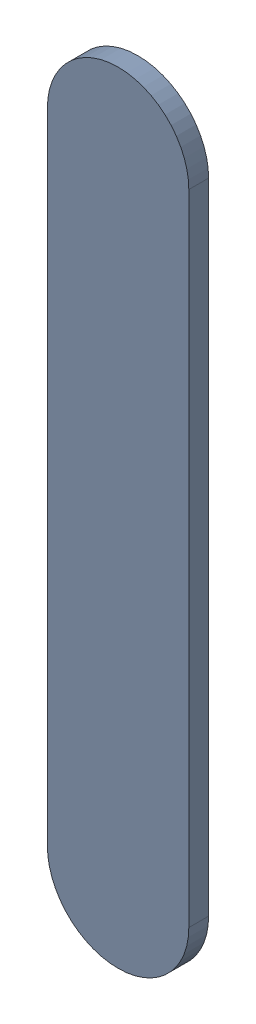
SolidWorks assembly Track (20.574mm,53.426mm)(20.574mm,54.574mm) on Bottom Layer, configuration Predeterminado. Lengths in mm.
Overall size (0.25 1.4 0.04).
2 component instances, 1 part files, 0 mates.
Components (placement in the parent):
- Track (20.574mm,53.426mm)(20.574mm,54.574mm) on Bottom Layer-1-1: Track (20.574mm,53.426mm)(20.574mm,54.574mm) on Bottom Layer-1 [Predeterminado] at (-68.317 -44.187 -0.4013) size (0.25 1.4 0.04)
  - Track (20.574mm,53.426mm)(20.574mm,54.574mm) on Bottom Layer-Part-1-1: Track (20.574mm,53.426mm)(20.574mm,54.574mm) on Bottom Layer-Part-1 [Predeterminado] at origin size (0.25 1.4 0.04)
